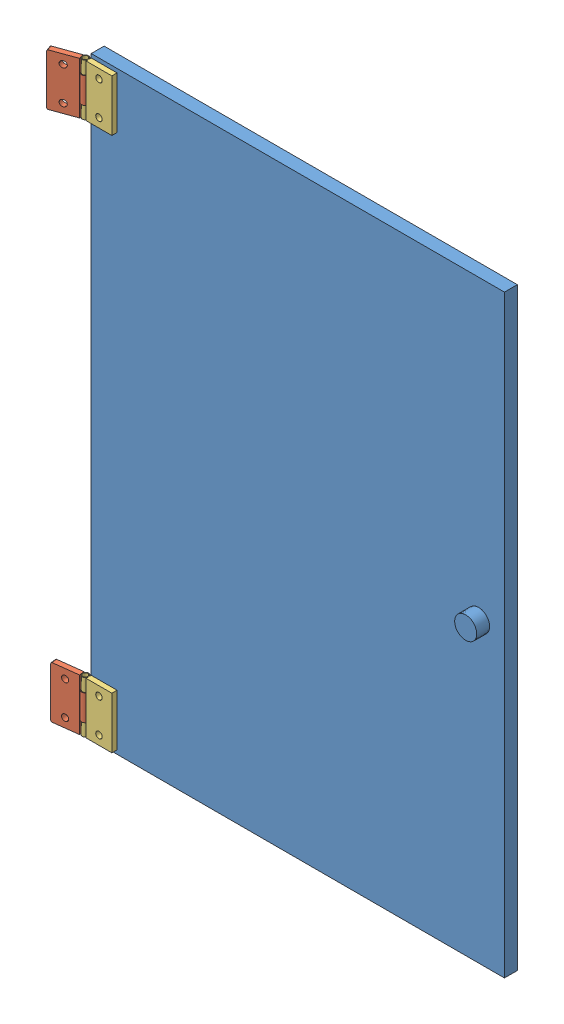
SolidWorks assembly door, configuration Default. Lengths in mm.
Overall size (345.2 460 22.45).
5 component instances, 3 part files, 10 mates.
Components (placement in the parent):
- glass-1: glass [Default] at (265.3341 251.2895 348.813) size (320 460 20)
- hinge1-1: hinge1 [Default] at (91.0742 458.2895 365.0537) x (0 1 0) z (0.338985 0 0.940792) size (40 25.5 6)
- hinge2-1: hinge2 [Default] at (115.3341 458.2895 360.813) x (0 1 0) z (0 0 -1) size (40 25 5)
- hinge2-2: hinge2 [Default] at (115.3341 44.2895 360.813) x (0 1 0) z (0 0 -1) size (40 25 5)
- hinge1-2: hinge1 [Default] at (90.4289 44.2895 362.353) x (0 1 0) z (0.122936 0 0.992415) size (40 25.5 6)
Mates (geometry in assembly coordinates):
- Concentric2: concentric: cylinder of hinge1-1 through (102.8341 468.2895 360.8164) axis (0 -1 0) radius 2; cylinder of hinge2-1 through (102.8341 478.2895 360.8164) axis (0 -1 0) radius 2
- Coincident2: coincident: plane of hinge1-1 through (102.8341 468.2895 360.8164) normal (0 1 0); plane of hinge2-1 through (105.3341 468.2895 363.813) normal (0 -1 0)
- Coincident4: coincident: plane of glass-1 through (265.3341 251.2895 358.813) normal (0 0 1); plane of hinge2-1 through (115.3341 458.2895 358.813) normal (0 0 -1)
- Concentric3: concentric: circle of glass-1; circle of hinge2-1
- Coincident5: coincident: cylinder of glass-1 through (115.3341 471.2895 358.813) axis (0 0 -1) radius 2.5; circle of hinge2-1
- Concentric6: concentric: cylinder of hinge2-2 through (102.8341 64.2895 360.8164) axis (0 -1 0) radius 2; cylinder of hinge1-2 through (102.8341 54.2895 360.8164) axis (0 -1 0) radius 2
- Coincident6: coincident: plane of hinge2-2 through (105.3341 54.2895 363.813) normal (0 -1 0); plane of hinge1-2 through (102.8341 54.2895 360.8164) normal (0 1 0)
- Coincident7: coincident: plane of glass-1 through (265.3341 251.2895 358.813) normal (0 0 1); plane of hinge2-2 through (115.3341 44.2895 358.813) normal (0 0 -1)
- Coincident8: coincident: circle of glass-1; circle of hinge2-2
- Coincident9: coincident: circle of glass-1; circle of hinge2-2
